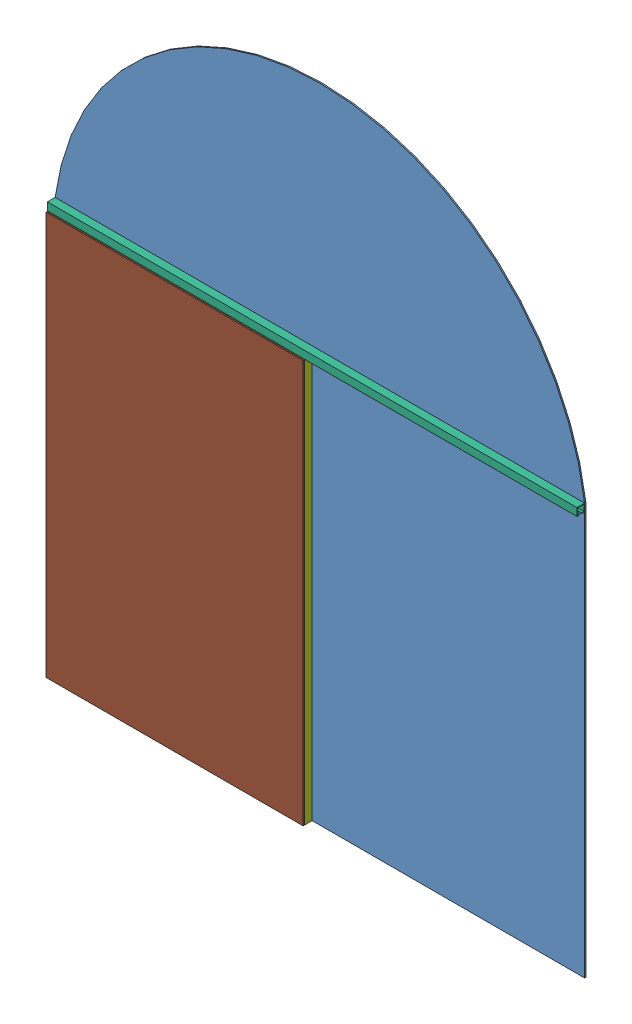
SolidWorks assembly FullFront, configuration Default. Lengths in mm.
Overall size (2060 2500 40).
35 component instances, 11 part files, 9 mates.
Components (placement in the parent):
- Front_SolarDryer-1: Front_SolarDryer [Default] at origin size (2060 2500 5)
- FullDoorWithBar-1: FullDoorWithBar [Default] at (0 785 17.5) x (0 0 1) z (-1 0 0) size (30 1600 2060)
  - FullCar-1: FullCar [Default] at (0 -6.25 870) size (25 18.99 35)
    - Carriage-1: Carriage [Default] at origin size (24.16 8.5 35)
    - LockWheels-1: LockWheels [Default] at (12.5 0 7.5) x (0 0.86398 0.503526) z (0 -0.503526 0.86398) size (3.5 7.63 3.5)
    - LockWheels-2: LockWheels [Default] at (12.5 0 -7.5) x (0 -0.86398 0.503526) z (0 -0.503526 -0.86398) size (3.5 7.63 3.5)
    - LockWheels-3: LockWheels [Default] at (-12.5 0 7.5) x (0 -0.86398 -0.503526) z (0 -0.503526 0.86398) size (3.5 7.63 3.5)
    - LockWheels-4: LockWheels [Default] at (-12.5 0 -7.5) x (0 0.86398 -0.503526) z (0 -0.503526 -0.86398) size (3.5 7.63 3.5)
    - WheelCarriage-1: WheelCarriage [Default] at (9.25 0 7.5) x (0 -0.862763 -0.505608) z (1 0 0) size (13.5 13.5 3.5)
    - WheelCarriage-2: WheelCarriage [Default] at (9.25 0 -7.5) x (0 -0.862763 0.505608) z (-1 0 0) size (13.5 13.5 3.5)
    - WheelCarriage-3: WheelCarriage [Default] at (-9.25 0 7.5) x (0 -0.862763 -0.505608) z (1 0 0) size (13.5 13.5 3.5)
    - WheelCarriage-4: WheelCarriage [Default] at (-9.25 0 -7.5) x (0 -0.862763 0.505608) z (-1 0 0) size (13.5 13.5 3.5)
    - Support-1: Support [Default] at (0 -7.5 0) x (0 0 1) z (-1 0 0) size (13 7.5 7)
  - FrontHorizontalBar-1: FrontHorizontalBar [Default] at origin size (30 30 2060)
  - Door-1: Door [Default] at (0 -801.125 530) x (0 0 1) z (-1 0 0) size (1000 1572.75 30)
  - Lid_Locker-1: Lid_Locker [Default] at (-3.725 -13.75 870) x (0 0 1) z (-1 0 0) size (13.9 5.5 1.7)
  - FullCar-4: FullCar [Default] at (0 -6.25 190) size (25 18.99 35)
    - Carriage-1: Carriage [Default] at origin size (24.16 8.5 35)
    - LockWheels-1: LockWheels [Default] at (12.5 0 7.5) x (0 0.86398 0.503526) z (0 -0.503526 0.86398) size (3.5 7.63 3.5)
    - LockWheels-2: LockWheels [Default] at (12.5 0 -7.5) x (0 -0.86398 0.503526) z (0 -0.503526 -0.86398) size (3.5 7.63 3.5)
    - LockWheels-3: LockWheels [Default] at (-12.5 0 7.5) x (0 -0.86398 -0.503526) z (0 -0.503526 0.86398) size (3.5 7.63 3.5)
    - LockWheels-4: LockWheels [Default] at (-12.5 0 -7.5) x (0 0.86398 -0.503526) z (0 -0.503526 -0.86398) size (3.5 7.63 3.5)
    - WheelCarriage-1: WheelCarriage [Default] at (9.25 0 7.5) x (0 -0.862763 -0.505608) z (1 0 0) size (13.5 13.5 3.5)
    - WheelCarriage-2: WheelCarriage [Default] at (9.25 0 -7.5) x (0 -0.862763 0.505608) z (-1 0 0) size (13.5 13.5 3.5)
    - WheelCarriage-3: WheelCarriage [Default] at (-9.25 0 7.5) x (0 -0.862763 -0.505608) z (1 0 0) size (13.5 13.5 3.5)
    - WheelCarriage-4: WheelCarriage [Default] at (-9.25 0 -7.5) x (0 -0.862763 0.505608) z (-1 0 0) size (13.5 13.5 3.5)
    - Support-1: Support [Default] at (0 -7.5 0) x (0 0 1) z (-1 0 0) size (13 7.5 7)
  - Lid_Locker-2: Lid_Locker [Default] at (-3.725 -13.75 190) x (0 0 1) z (-1 0 0) size (13.9 5.5 1.7)
  - Full_Restrictor-1: Full_Restrictor [Default] at (0 -12.75 897.6) x (-1 0 0) z (0 0 -1) size (25 10.16 20.1)
    - Lid_Restrictor-1: Lid_Restrictor [Default] at (0 8.5 10.1) x (1 0 0) z (0 0 -1) size (2.81 2.81 3)
    - Restrictor-1: Restrictor [Default] at origin size (25 9.5 19.9)
  - Full_Restrictor-2: Full_Restrictor [Default] at (0 -12.75 -897.6) size (25 10.16 20.1)
    - Lid_Restrictor-1: Lid_Restrictor [Default] at (0 8.5 10.1) x (1 0 0) z (0 0 -1) size (2.81 2.81 3)
    - Restrictor-1: Restrictor [Default] at origin size (25 9.5 19.9)
- DoorCover-1: DoorCover [Default] at (-530 -16.125 35) size (1000 1567.75 5)
Mates (geometry in assembly coordinates):
- Coincident2: coincident aligned: plane of Front_SolarDryer-1 through (0 0 0) normal (0 0 1)
- Coincident3: coincident aligned: plane of Front_SolarDryer-1 through (0 0 0) normal (0 1 0)
- Coincident4: coincident aligned: plane of Front_SolarDryer-1 through (0 0 0) normal (1 0 0)
- Coincident5: coincident anti-aligned: plane of Front_SolarDryer-1 through (0 660.6111 2.5) normal (0 0 1); plane of FullDoorWithBar-1/FrontHorizontalBar-1 through (-1030 770 2.5) normal (0 0 -1)
- Coincident6: coincident aligned: line of Front_SolarDryer-1 through (-1030 770 2.5) axis (1 0 0); line of FullDoorWithBar-1/FrontHorizontalBar-1 through (-1030 770 2.5) axis (1 0 0)
- Coincident7: coincident aligned: plane of Front_SolarDryer-1 through (-1030 800 2.5) normal (-1 0 0); plane of FullDoorWithBar-1/FrontHorizontalBar-1 through (-1030 785 17.5) normal (-1 0 0)
- Coincident8: coincident: plane of FullDoorWithBar-1/Door-1 through (-530 -16.125 32.5) normal (0 0 1); plane of DoorCover-1 through (-530 -16.125 32.5) normal (0 0 -1)
- Coincident9: coincident: plane of FullDoorWithBar-1/Door-1 through (-1030 767.75 2.5) normal (-1 0 0); plane of DoorCover-1 through (-1030 767.75 37.5) normal (-1 0 0)
- Coincident10: coincident aligned: plane of FullDoorWithBar-1/Door-1 through (-30 767.75 2.5) normal (0 1 0); plane of DoorCover-1 through (-30 767.75 37.5) normal (0 1 0)
